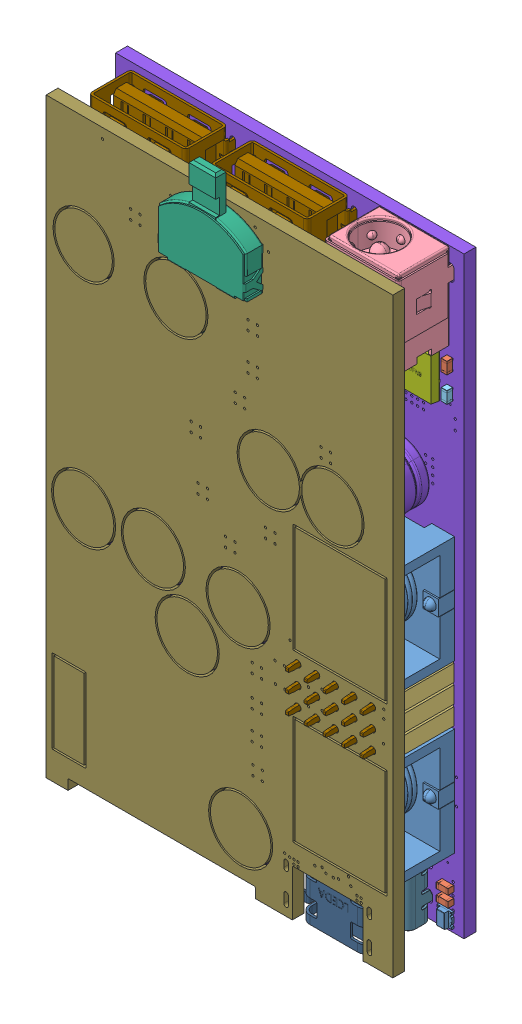
SolidWorks assembly YDS, configuration 默认. Lengths in mm.
Overall size (47.39 84.33 15.15).
408 component instances, 34 part files, 3 mates.
Components (placement in the parent):
- 3D_1_PCB_YDS-Charger_2022-04-09_2022-04-09-1: 3D_1_PCB_YDS-Charger_2022-04-09_2022-04-09 [Default] at (-64.0814 58.5784 -4.3265) size (47.39 99.44 11.55)
  - 3D_1_PCB_YDS-Charger_2022-04-09_2022-04-09.step-1: 3D_1_PCB_YDS-Charger_2022-04-09_2022-04-09.step [Default] at origin size (47.39 99.44 11.55)
    - LED1.step-1: LED1.step [Default] at (44.6406 -78.4544 1.6) x (-1 0 0) z (0 0 1) size (2 2 0.84)
      - LED-SMD_4P-L2.0-W2.0-TL_WS2812B-2020.step-1: LED-SMD_4P-L2.0-W2.0-TL_WS2812B-2020.step [Default] at (0 0.0001 0.02) size (2 2 0.84)
        - COMPOUND.step-1: COMPOUND.step [Default] at origin size (2 2 0.84)
    - LED2.step-1: LED2.step [Default] at (31.5596 -78.4544 1.6) x (-1 0 0) z (0 0 1) size (2 2 0.84)
      - LED-SMD_4P-L2.0-W2.0-TL_WS2812B-2020.step-1: LED-SMD_4P-L2.0-W2.0-TL_WS2812B-2020.step [Default] at (0 0.0001 0.02) size (2 2 0.84)
        - COMPOUND.step-1: COMPOUND.step [Default] at origin size (2 2 0.84)
    - C28.step-1: C28.step [Default] at (29.8451 -61.5951 1.6) x (0 1 0) z (0 0 1) size (1.6 0.8 0.8)
      - C0603.step-1: C0603.step [Default] at (0 0 0.4) size (1.6 0.8 0.8)
        - SOLID.step-1: SOLID.step [Default] at origin size (1.6 0.8 0.8)
    - C49.step-1: C49.step [Default] at (19.05 -42.6721 1.6) x (-0.707107 0.707107 0) z (0 0 1) size (1.6 0.8 0.8)
      - C0603.step-1: C0603.step [Default] at (0 0 0.4) size (1.6 0.8 0.8)
        - SOLID.step-1: SOLID.step [Default] at origin size (1.6 0.8 0.8)
    - C51.step-1: C51.step [Default] at (24.645 -14.859 1.6) x (-1 0 0) z (0 0 1) size (1.6 0.8 0.8)
      - C0603.step-1: C0603.step [Default] at (0 0 0.4) size (1.6 0.8 0.8)
        - SOLID.step-1: SOLID.step [Default] at origin size (1.6 0.8 0.8)
    - C38.step-1: C38.step [Default] at (30.9246 -50.2921 1.6) size (1.6 0.8 0.8)
      - C0603.step-1: C0603.step [Default] at (0 0 0.4) size (1.6 0.8 0.8)
        - SOLID.step-1: SOLID.step [Default] at origin size (1.6 0.8 0.8)
    - C54.step-1: C54.step [Default] at (17.653 -60.4521 1.6) size (1.6 0.8 0.8)
      - C0603.step-1: C0603.step [Default] at (0 0 0.4) size (1.6 0.8 0.8)
        - SOLID.step-1: SOLID.step [Default] at origin size (1.6 0.8 0.8)
    - C46.step-1: C46.step [Default] at (11.557 -14.859 1.6) x (-1 0 0) z (0 0 1) size (1.6 0.8 0.8)
      - C0603.step-1: C0603.step [Default] at (0 0 0.4) size (1.6 0.8 0.8)
        - SOLID.step-1: SOLID.step [Default] at origin size (1.6 0.8 0.8)
    - C26.step-1: C26.step [Default] at (44.8311 -76.3271 1.6) x (-1 0 0) z (0 0 1) size (1.6 0.8 0.8)
      - C0603.step-1: C0603.step [Default] at (0 0 0.4) size (1.6 0.8 0.8)
        - SOLID.step-1: SOLID.step [Default] at origin size (1.6 0.8 0.8)
    - C27.step-1: C27.step [Default] at (44.8311 -74.8031 1.6) x (-1 0 0) z (0 0 1) size (1.6 0.8 0.8)
      - C0603.step-1: C0603.step [Default] at (0 0 0.4) size (1.6 0.8 0.8)
        - SOLID.step-1: SOLID.step [Default] at origin size (1.6 0.8 0.8)
    - C29.step-1: C29.step [Default] at (29.2101 -76.9304 1.6) x (0.866025 0.5 0) z (0 0 1) size (1.6 0.8 0.8)
      - C0603.step-1: C0603.step [Default] at (0 0 0.4) size (1.6 0.8 0.8)
        - SOLID.step-1: SOLID.step [Default] at origin size (1.6 0.8 0.8)
    - C39.step-1: C39.step [Default] at (29.7181 -38.5091 1.6) x (0 1 0) z (0 0 1) size (1.6 0.8 0.8)
      - C0603.step-1: C0603.step [Default] at (0 0 0.4) size (1.6 0.8 0.8)
        - SOLID.step-1: SOLID.step [Default] at origin size (1.6 0.8 0.8)
    - C22.step-1: C22.step [Default] at (9.398 -42.5451 1.6) x (-0.707107 0.707107 0) z (0 0 1) size (1.6 0.8 0.8)
      - C0603.step-1: C0603.step [Default] at (0 0 0.4) size (1.6 0.8 0.8)
        - SOLID.step-1: SOLID.step [Default] at origin size (1.6 0.8 0.8)
    - C45.step-1: C45.step [Default] at (3.048 -40.1321 1.6) x (0 1 0) z (0 0 1) size (1.6 0.8 0.8)
      - C0603.step-1: C0603.step [Default] at (0 0 0.4) size (1.6 0.8 0.8)
        - SOLID.step-1: SOLID.step [Default] at origin size (1.6 0.8 0.8)
    - C47.step-1: C47.step [Default] at (3.0425 -33.9526 1.6) x (0 -1 0) z (0 0 1) size (1.6 0.8 0.8)
      - C0603.step-1: C0603.step [Default] at (0 0 0.4) size (1.6 0.8 0.8)
        - SOLID.step-1: SOLID.step [Default] at origin size (1.6 0.8 0.8)
    - C48.step-1: C48.step [Default] at (12.0333 -33.9526 1.6) x (0 -1 0) z (0 0 1) size (1.6 0.8 0.8)
      - C0603.step-1: C0603.step [Default] at (0 0 0.4) size (1.6 0.8 0.8)
        - SOLID.step-1: SOLID.step [Default] at origin size (1.6 0.8 0.8)
    - C52.step-1: C52.step [Default] at (12.0386 -40.1321 1.6) x (0 1 0) z (0 0 1) size (1.6 0.8 0.8)
      - C0603.step-1: C0603.step [Default] at (0 0 0.4) size (1.6 0.8 0.8)
        - SOLID.step-1: SOLID.step [Default] at origin size (1.6 0.8 0.8)
    - C13.step-1: C13.step [Default] at (8.763 -73.7871 1.6) x (0 1 0) z (0 0 1) size (1.6 0.8 0.8)
      - C0603.step-1: C0603.step [Default] at (0 0 0.4) size (1.6 0.8 0.8)
        - SOLID.step-1: SOLID.step [Default] at origin size (1.6 0.8 0.8)
    - C6.step-1: C6.step [Default] at (21.59 -76.9621 1.6) x (0 -1 0) z (0 0 1) size (1.6 0.8 0.8)
      - C0603.step-1: C0603.step [Default] at (0 0 0.4) size (1.6 0.8 0.8)
        - SOLID.step-1: SOLID.step [Default] at origin size (1.6 0.8 0.8)
    - C58.step-1: C58.step [Default] at (5.715 -51.4351 1.6) size (1.6 0.8 0.8)
      - C0603.step-1: C0603.step [Default] at (0 0 0.4) size (1.6 0.8 0.8)
        - SOLID.step-1: SOLID.step [Default] at origin size (1.6 0.8 0.8)
    - C40.step-1: C40.step [Default] at (21.971 -41.0491 1.6) size (1.6 0.8 0.8)
      - C0603.step-1: C0603.step [Default] at (0 0 0.4) size (1.6 0.8 0.8)
        - SOLID.step-1: SOLID.step [Default] at origin size (1.6 0.8 0.8)
    - C24.step-1: C24.step [Default] at (26.7971 -65.2781 1.6) size (1.6 0.8 0.8)
      - C0603.step-1: C0603.step [Default] at (-0.0001 0 0.4) size (1.6 0.8 0.8)
        - SOLID.step-1: SOLID.step [Default] at origin size (1.6 0.8 0.8)
    - C30.step-1: C30.step [Default] at (29.0831 -58.0671 1.6) size (1.6 0.8 0.8)
      - C0603.step-1: C0603.step [Default] at (0 0 0.4) size (1.6 0.8 0.8)
        - SOLID.step-1: SOLID.step [Default] at origin size (1.6 0.8 0.8)
    - C31.step-1: C31.step [Default] at (25.6541 -58.0671 1.6) size (1.6 0.8 0.8)
      - C0603.step-1: C0603.step [Default] at (0 0 0.4) size (1.6 0.8 0.8)
        - SOLID.step-1: SOLID.step [Default] at origin size (1.6 0.8 0.8)
    - C32.step-1: C32.step [Default] at (22.86 -62.0041 1.6) x (0 1 0) z (0 0 1) size (1.6 0.8 0.8)
      - C0603.step-1: C0603.step [Default] at (0 0 0.4) size (1.6 0.8 0.8)
        - SOLID.step-1: SOLID.step [Default] at origin size (1.6 0.8 0.8)
    - C35.step-1: C35.step [Default] at (21.971 -37.4931 1.6) size (1.6 0.8 0.8)
      - C0603.step-1: C0603.step [Default] at (-0.0001 0 0.4) size (1.6 0.8 0.8)
        - SOLID.step-1: SOLID.step [Default] at origin size (1.6 0.8 0.8)
    - C36.step-1: C36.step [Default] at (27.9401 -34.163 1.6) x (0 1 0) z (0 0 1) size (1.6 0.8 0.8)
      - C0603.step-1: C0603.step [Default] at (0 -0.0001 0.4) size (1.6 0.8 0.8)
        - SOLID.step-1: SOLID.step [Default] at origin size (1.6 0.8 0.8)
    - C37.step-1: C37.step [Default] at (29.7181 -35.4611 1.6) x (0 -1 0) z (0 0 1) size (1.6 0.8 0.8)
      - C0603.step-1: C0603.step [Default] at (0 0.0001 0.4) size (1.6 0.8 0.8)
        - SOLID.step-1: SOLID.step [Default] at origin size (1.6 0.8 0.8)
    - C41.step-1: C41.step [Default] at (21.971 -39.2711 1.6) size (1.6 0.8 0.8)
      - C0603.step-1: C0603.step [Default] at (0 0 0.4) size (1.6 0.8 0.8)
        - SOLID.step-1: SOLID.step [Default] at origin size (1.6 0.8 0.8)
    - C43.step-1: C43.step [Default] at (24.638 -53.0861 1.6) x (0 1 0) z (0 0 1) size (1.6 0.8 0.8)
      - C0603.step-1: C0603.step [Default] at (0 -0.0001 0.4) size (1.6 0.8 0.8)
        - SOLID.step-1: SOLID.step [Default] at origin size (1.6 0.8 0.8)
    - C7.step-1: C7.step [Default] at (20.828 -73.1521 1.6) size (1.6 0.8 0.8)
      - C0603.step-1: C0603.step [Default] at (0 0 0.4) size (1.6 0.8 0.8)
        - SOLID.step-1: SOLID.step [Default] at origin size (1.6 0.8 0.8)
    - C14.step-1: C14.step [Default] at (10.414 -73.7871 1.6) x (0 1 0) z (0 0 1) size (1.6 0.8 0.8)
      - C0603.step-1: C0603.step [Default] at (0 0 0.4) size (1.6 0.8 0.8)
        - SOLID.step-1: SOLID.step [Default] at origin size (1.6 0.8 0.8)
    - C15.step-1: C15.step [Default] at (14.986 -67.2112 1.6) x (-1 0 0) z (0 0 1) size (1.6 0.8 0.8)
      - C0603.step-1: C0603.step [Default] at (0 0 0.4) size (1.6 0.8 0.8)
        - SOLID.step-1: SOLID.step [Default] at origin size (1.6 0.8 0.8)
    - C16.step-1: C16.step [Default] at (18.034 -67.2112 1.6) size (1.6 0.8 0.8)
      - C0603.step-1: C0603.step [Default] at (0 0 0.4) size (1.6 0.8 0.8)
        - SOLID.step-1: SOLID.step [Default] at origin size (1.6 0.8 0.8)
    - C17.step-1: C17.step [Default] at (18.288 -76.9621 1.6) x (0 1 0) z (0 0 1) size (1.6 0.8 0.8)
      - C0603.step-1: C0603.step [Default] at (0 0 0.4) size (1.6 0.8 0.8)
        - SOLID.step-1: SOLID.step [Default] at origin size (1.6 0.8 0.8)
    - C18.step-1: C18.step [Default] at (15.875 -76.2001 1.6) size (1.6 0.8 0.8)
      - C0603.step-1: C0603.step [Default] at (0 0 0.4) size (1.6 0.8 0.8)
        - SOLID.step-1: SOLID.step [Default] at origin size (1.6 0.8 0.8)
    - C19.step-1: C19.step [Default] at (6.096 -71.1482 1.6) x (0 -1 0) z (0 0 1) size (1.6 0.8 0.8)
      - C0603.step-1: C0603.step [Default] at (0 0 0.4) size (1.6 0.8 0.8)
        - SOLID.step-1: SOLID.step [Default] at origin size (1.6 0.8 0.8)
    - C20.step-1: C20.step [Default] at (6.096 -67.9732 1.6) x (0 1 0) z (0 0 1) size (1.6 0.8 0.8)
      - C0603.step-1: C0603.step [Default] at (0 0 0.4) size (1.6 0.8 0.8)
        - SOLID.step-1: SOLID.step [Default] at origin size (1.6 0.8 0.8)
    - C55.step-1: C55.step [Default] at (9.525 -55.1181 1.6) size (1.6 0.8 0.8)
      - C0603.step-1: C0603.step [Default] at (0 0 0.4) size (1.6 0.8 0.8)
        - SOLID.step-1: SOLID.step [Default] at origin size (1.6 0.8 0.8)
    - C56.step-1: C56.step [Default] at (9.525 -56.8961 1.6) x (-1 0 0) z (0 0 1) size (1.6 0.8 0.8)
      - C0603.step-1: C0603.step [Default] at (0 0 0.4) size (1.6 0.8 0.8)
        - SOLID.step-1: SOLID.step [Default] at origin size (1.6 0.8 0.8)
    - C57.step-1: C57.step [Default] at (9.906 -49.7841 1.6) size (1.6 0.8 0.8)
      - C0603.step-1: C0603.step [Default] at (0 0 0.4) size (1.6 0.8 0.8)
        - SOLID.step-1: SOLID.step [Default] at origin size (1.6 0.8 0.8)
    - C2.step-1: C2.step [Default] at (3.937 -63.5001 1.6) x (0 1 0) z (0 0 1) size (1.6 0.8 0.8)
      - C0603.step-1: C0603.step [Default] at (0 0 0.4) size (1.6 0.8 0.8)
        - SOLID.step-1: SOLID.step [Default] at origin size (1.6 0.8 0.8)
    - C3.step-1: C3.step [Default] at (2.413 -63.5001 1.6) x (0 1 0) z (0 0 1) size (1.6 0.8 0.8)
      - C0603.step-1: C0603.step [Default] at (0 0 0.4) size (1.6 0.8 0.8)
        - SOLID.step-1: SOLID.step [Default] at origin size (1.6 0.8 0.8)
    - C8.step-1: C8.step [Default] at (5.461 -63.5001 1.6) x (0 1 0) z (0 0 1) size (1.6 0.8 0.8)
      - C0603.step-1: C0603.step [Default] at (0 0 0.4) size (1.6 0.8 0.8)
        - SOLID.step-1: SOLID.step [Default] at origin size (1.6 0.8 0.8)
    - C9.step-1: C9.step [Default] at (6.985 -63.5001 1.6) x (0 1 0) z (0 0 1) size (1.6 0.8 0.8)
      - C0603.step-1: C0603.step [Default] at (0 0 0.4) size (1.6 0.8 0.8)
        - SOLID.step-1: SOLID.step [Default] at origin size (1.6 0.8 0.8)
    - C10.step-1: C10.step [Default] at (22.733 -65.3061 1.6) x (0 1 0) z (0 0 1) size (1.6 0.8 0.8)
      - C0603.step-1: C0603.step [Default] at (0 0 0.4) size (1.6 0.8 0.8)
        - SOLID.step-1: SOLID.step [Default] at origin size (1.6 0.8 0.8)
    - C11.step-1: C11.step [Default] at (20.701 -65.3061 1.6) x (0 1 0) z (0 0 1) size (1.6 0.8 0.8)
      - C0603.step-1: C0603.step [Default] at (0 0 0.4) size (1.6 0.8 0.8)
        - SOLID.step-1: SOLID.step [Default] at origin size (1.6 0.8 0.8)
    - C12.step-1: C12.step [Default] at (10.795 -64.2901 1.6) x (-1 0 0) z (0 0 1) size (1.6 0.8 0.8)
      - C0603.step-1: C0603.step [Default] at (0 0 0.4) size (1.6 0.8 0.8)
        - SOLID.step-1: SOLID.step [Default] at origin size (1.6 0.8 0.8)
    - C63.step-1: C63.step [Default] at (45.0851 -13.716 1.6) x (0 1 0) z (0 0 1) size (1.6 0.8 0.8)
      - C0603.step-1: C0603.step [Default] at (0 0 0.4) size (1.6 0.8 0.8)
        - SOLID.step-1: SOLID.step [Default] at origin size (1.6 0.8 0.8)
    - C53.step-1: C53.step [Default] at (13.97 -56.0072 1.6) x (0 -1 0) z (0 0 1) size (1.6 0.8 0.8)
      - C0603.step-1: C0603.step [Default] at (0 0 0.4) size (1.6 0.8 0.8)
        - SOLID.step-1: SOLID.step [Default] at origin size (1.6 0.8 0.8)
    - U3.step-1: U3.step [Default] at (7.366 -36.957 1.6) x (-1 0 0) z (0 0 1) size (4.9 3.9 1.6)
      - ESOP-8_L4.9-W3.9-P1.27-LS6.0-BL-EP.step-1: ESOP-8_L4.9-W3.9-P1.27-LS6.0-BL-EP.step [Default] at (0 0 0.0993) x (0 1 0) z (0 0 1) size (3.9 4.9 1.6)
        - =_[0_1_1_59].step-1: =_[0_1_1_59].step [Default] at origin size (3.9 4.9 1.6)
    - U8.step-1: U8.step [Default] at (15.621 -36.9851 1.6) x (-1 0 0) z (0 0 1) size (4.9 3.9 1.6)
      - ESOP-8_L4.9-W3.9-P1.27-LS6.0-BL-EP.step-1: ESOP-8_L4.9-W3.9-P1.27-LS6.0-BL-EP.step [Default] at (0 0 0.0993) x (0 1 0) z (0 0 1) size (3.9 4.9 1.6)
        - =_[0_1_1_59].step-1: =_[0_1_1_59].step [Default] at origin size (3.9 4.9 1.6)
    - C33.step-1: C33.step [Default] at (20.828 -61.6231 1.6) x (0 1 0) z (0 0 1) size (2 1.3 1.3)
      - C0805.step-1: C0805.step [Default] at (0 0 0.65) size (2 1.3 1.3)
        - SOLID-0.step-1: SOLID-0.step [Default] at origin size (2 1.3 1.3)
    - C34.step-1: C34.step [Default] at (24.13 -12.954 1.6) size (2 1.3 1.3)
      - C0805.step-1: C0805.step [Default] at (0 0.0001 0.65) size (2 1.3 1.3)
        - SOLID-0.step-1: SOLID-0.step [Default] at origin size (2 1.3 1.3)
    - C62.step-1: C62.step [Default] at (11.684 -12.954 1.6) x (-1 0 0) z (0 0 1) size (2 1.3 1.3)
      - C0805.step-1: C0805.step [Default] at (0 0 0.65) size (2 1.3 1.3)
        - SOLID-0.step-1: SOLID-0.step [Default] at origin size (2 1.3 1.3)
    - C42.step-1: C42.step [Default] at (26.7971 -53.4671 1.6) x (0 1 0) z (0 0 1) size (2 1.3 1.3)
      - C0805.step-1: C0805.step [Default] at (0 0 0.65) size (2 1.3 1.3)
        - SOLID-0.step-1: SOLID-0.step [Default] at origin size (2 1.3 1.3)
    - C25.step-1: C25.step [Default] at (28.5751 -67.4371 1.6) size (2 1.3 1.3)
      - C0805.step-1: C0805.step [Default] at (0 0.0001 0.65) size (2 1.3 1.3)
        - SOLID-0.step-1: SOLID-0.step [Default] at origin size (2 1.3 1.3)
    - C23.step-1: C23.step [Default] at (21.717 -35.2071 1.6) size (2 1.3 1.3)
      - C0805.step-1: C0805.step [Default] at (0 0 0.65) size (2 1.3 1.3)
        - SOLID-0.step-1: SOLID-0.step [Default] at origin size (2 1.3 1.3)
    - C64.step-1: C64.step [Default] at (36.0681 -18.669 1.6) x (-1 0 0) z (0 0 1) size (2 1.3 1.3)
      - C0805.step-1: C0805.step [Default] at (0 0 0.65) size (2 1.3 1.3)
        - SOLID-0.step-1: SOLID-0.step [Default] at origin size (2 1.3 1.3)
    - R2.step-1: R2.step [Default] at (29.8451 -64.5161 1.6) x (0 -1 0) z (0 0 1) size (1.6 0.8 0.8)
      - R0603.step-1: R0603.step [Default] at (0 0 0.4) size (1.6 0.8 0.8)
        - SOLID-1.step-1: SOLID-1.step [Default] at origin size (1.6 0.8 0.8)
    - R15.step-1: R15.step [Default] at (29.7181 -41.5571 1.6) x (0 -1 0) z (0 0 1) size (1.6 0.8 0.8)
      - R0603.step-1: R0603.step [Default] at (0 -0.0001 0.4) size (1.6 0.8 0.8)
        - SOLID-1.step-1: SOLID-1.step [Default] at origin size (1.6 0.8 0.8)
    - R16.step-1: R16.step [Default] at (3.048 -37.084 1.6) x (0 -1 0) z (0 0 1) size (1.6 0.8 0.8)
      - R0603.step-1: R0603.step [Default] at (0 0 0.4) size (1.6 0.8 0.8)
        - SOLID-1.step-1: SOLID-1.step [Default] at origin size (1.6 0.8 0.8)
    - R13.step-1: R13.step [Default] at (12.0333 -37.0523 1.6) x (0 -1 0) z (0 0 1) size (1.6 0.8 0.8)
      - R0603.step-1: R0603.step [Default] at (0 0 0.4) size (1.6 0.8 0.8)
        - SOLID-1.step-1: SOLID-1.step [Default] at origin size (1.6 0.8 0.8)
    - R1.step-1: R1.step [Default] at (20.828 -74.6761 1.6) x (-1 0 0) z (0 0 1) size (1.6 0.8 0.8)
      - R0603.step-1: R0603.step [Default] at (0 0 0.4) size (1.6 0.8 0.8)
        - SOLID-1.step-1: SOLID-1.step [Default] at origin size (1.6 0.8 0.8)
    - R6.step-1: R6.step [Default] at (19.939 -76.9621 1.6) x (0 -1 0) z (0 0 1) size (1.6 0.8 0.8)
      - R0603.step-1: R0603.step [Default] at (0 0 0.4) size (1.6 0.8 0.8)
        - SOLID-1.step-1: SOLID-1.step [Default] at origin size (1.6 0.8 0.8)
    - R4.step-1: R4.step [Default] at (20.828 -70.2311 1.6) size (1.6 0.8 0.8)
      - R0603.step-1: R0603.step [Default] at (0 0 0.4) size (1.6 0.8 0.8)
        - SOLID-1.step-1: SOLID-1.step [Default] at origin size (1.6 0.8 0.8)
    - R5.step-1: R5.step [Default] at (23.0188 -58.7058 1.6) x (0 1 0) z (0 0 1) size (1.6 0.8 0.8)
      - R0603.step-1: R0603.step [Default] at (0 0 0.4) size (1.6 0.8 0.8)
        - SOLID-1.step-1: SOLID-1.step [Default] at origin size (1.6 0.8 0.8)
    - R12.step-1: R12.step [Default] at (25.5271 -34.925 1.6) size (1.6 0.8 0.8)
      - R0603.step-1: R0603.step [Default] at (0.0001 0 0.4) size (1.6 0.8 0.8)
        - SOLID-1.step-1: SOLID-1.step [Default] at origin size (1.6 0.8 0.8)
    - R7.step-1: R7.step [Default] at (8.509 -63.5281 1.6) x (0 1 0) z (0 0 1) size (1.6 0.8 0.8)
      - R0603.step-1: R0603.step [Default] at (0 0 0.4) size (1.6 0.8 0.8)
        - SOLID-1.step-1: SOLID-1.step [Default] at origin size (1.6 0.8 0.8)
    - R8.step-1: R8.step [Default] at (14.605 -63.5485 1.6) x (0 -1 0) z (0 0 1) size (1.6 0.8 0.8)
      - R0603.step-1: R0603.step [Default] at (0 0 0.4) size (1.6 0.8 0.8)
        - SOLID-1.step-1: SOLID-1.step [Default] at origin size (1.6 0.8 0.8)
    - R9.step-1: R9.step [Default] at (13.081 -63.5485 1.6) x (0 1 0) z (0 0 1) size (1.6 0.8 0.8)
      - R0603.step-1: R0603.step [Default] at (0 0 0.4) size (1.6 0.8 0.8)
        - SOLID-1.step-1: SOLID-1.step [Default] at origin size (1.6 0.8 0.8)
    - R10.step-1: R10.step [Default] at (20.828 -68.8341 1.6) x (-1 0 0) z (0 0 1) size (1.6 0.8 0.8)
      - R0603.step-1: R0603.step [Default] at (0 0 0.4) size (1.6 0.8 0.8)
        - SOLID-1.step-1: SOLID-1.step [Default] at origin size (1.6 0.8 0.8)
    - R11.step-1: R11.step [Default] at (10.795 -62.6391 1.6) x (-1 0 0) z (0 0 1) size (1.6 0.8 0.8)
      - R0603.step-1: R0603.step [Default] at (0 0 0.4) size (1.6 0.8 0.8)
        - SOLID-1.step-1: SOLID-1.step [Default] at origin size (1.6 0.8 0.8)
    - R19.step-1: R19.step [Default] at (45.0851 -17.145 1.6) x (0 -1 0) z (0 0 1) size (1.6 0.8 0.8)
      - R0603.step-1: R0603.step [Default] at (0 0 0.4) size (1.6 0.8 0.8)
        - SOLID-1.step-1: SOLID-1.step [Default] at origin size (1.6 0.8 0.8)
    - R20.step-1: R20.step [Default] at (32.2581 -18.669 1.6) x (-1 0 0) z (0 0 1) size (1.6 0.8 0.8)
      - R0603.step-1: R0603.step [Default] at (0 0 0.4) size (1.6 0.8 0.8)
        - SOLID-1.step-1: SOLID-1.step [Default] at origin size (1.6 0.8 0.8)
    - R21.step-1: R21.step [Default] at (36.3221 -20.574 1.6) x (-1 0 0) z (0 0 1) size (1.6 0.8 0.8)
      - R0603.step-1: R0603.step [Default] at (0 0 0.4) size (1.6 0.8 0.8)
        - SOLID-1.step-1: SOLID-1.step [Default] at origin size (1.6 0.8 0.8)
    - R22.step-1: R22.step [Default] at (11.557 -16.637 1.6) size (1.6 0.8 0.8)
      - R0603.step-1: R0603.step [Default] at (0 0 0.4) size (1.6 0.8 0.8)
        - SOLID-1.step-1: SOLID-1.step [Default] at origin size (1.6 0.8 0.8)
    - R23.step-1: R23.step [Default] at (11.557 -18.288 1.6) x (-1 0 0) z (0 0 1) size (1.6 0.8 0.8)
      - R0603.step-1: R0603.step [Default] at (0 0 0.4) size (1.6 0.8 0.8)
        - SOLID-1.step-1: SOLID-1.step [Default] at origin size (1.6 0.8 0.8)
    - R24.step-1: R24.step [Default] at (20.828 -71.5646 1.6) size (1.6 0.8 0.8)
      - R0603.step-1: R0603.step [Default] at (0 0 0.4) size (1.6 0.8 0.8)
        - SOLID-1.step-1: SOLID-1.step [Default] at origin size (1.6 0.8 0.8)
    - R25.step-1: R25.step [Default] at (24.7015 -16.4465 1.6) size (1.6 0.8 0.8)
      - R0603.step-1: R0603.step [Default] at (0 0 0.4) size (1.6 0.8 0.8)
        - SOLID-1.step-1: SOLID-1.step [Default] at origin size (1.6 0.8 0.8)
    - R26.step-1: R26.step [Default] at (24.7015 -18.034 1.6) x (-1 0 0) z (0 0 1) size (1.6 0.8 0.8)
      - R0603.step-1: R0603.step [Default] at (0 0 0.4) size (1.6 0.8 0.8)
        - SOLID-1.step-1: SOLID-1.step [Default] at origin size (1.6 0.8 0.8)
    - R17.step-1: R17.step [Default] at (12.446 -56.0071 1.6) x (0 1 0) z (0 0 1) size (1.6 0.8 0.8)
      - R0603.step-1: R0603.step [Default] at (0 0 0.4) size (1.6 0.8 0.8)
        - SOLID-1.step-1: SOLID-1.step [Default] at origin size (1.6 0.8 0.8)
    - R18.step-1: R18.step [Default] at (12.446 -52.8638 1.6) x (0 1 0) z (0 0 1) size (1.6 0.8 0.8)
      - R0603.step-1: R0603.step [Default] at (0 0 0.4) size (1.6 0.8 0.8)
        - SOLID-1.step-1: SOLID-1.step [Default] at origin size (1.6 0.8 0.8)
    - R14.step-1: R14.step [Default] at (30.3531 -52.4511 1.6) x (-1 0 0) z (0 0 1) size (3.2 1.6 0.56)
      - R1206.step-1: R1206.step [Default] at origin size (3.2 1.6 0.56)
        - COMPOUND-2.step-1: COMPOUND-2.step [Default] at origin size (3.2 1.6 0.56)
    - R3.step-1: R3.step [Default] at (31.7501 -74.0411 1.6) x (0 -1 0) z (0 0 1) size (3.2 1.6 0.56)
      - R1206.step-1: R1206.step [Default] at origin size (3.2 1.6 0.56)
        - COMPOUND-2.step-1: COMPOUND-2.step [Default] at origin size (3.2 1.6 0.56)
    - U9.step-1: U9.step [Default] at (17.653 -63.3731 1.6) size (3 3 0.92)
      - LGA-16_L3.0-W3.0-P0.50-TL.step-1: LGA-16_L3.0-W3.0-P0.50-TL.step [Default] at (0.0001 0.0001 0) size (3 3 0.92)
        - COMPOUND-3.step-1: COMPOUND-3.step [Default] at origin size (3 3 0.92)
    - C4.step-1: C4.step [Default] at (30.4166 -28.956 1.6) x (0.707107 0.707107 0) z (0 0 1) size (8 8 11.5)
      - CAP-TH_BD8.0-P3.50-D0.6-FD.step-1: CAP-TH_BD8.0-P3.50-D0.6-FD.step [Default] at (0.1475 0.1475 0.5) x (-1 0 0) z (0 0 1) size (8 8 11.5)
        - SOLID-4.step-1: SOLID-4.step [Default] at origin size (8 8 11.5)
    - C21.step-1: C21.step [Default] at (5.461 -15.113 1.6) x (-0.707107 0.707107 0) z (0 0 1) size (8 8 11.5)
      - CAP-TH_BD8.0-P3.50-D0.6-FD.step-1: CAP-TH_BD8.0-P3.50-D0.6-FD.step [Default] at (0.1475 0.1475 0.5) x (-1 0 0) z (0 0 1) size (8 8 11.5)
        - SOLID-4.step-1: SOLID-4.step [Default] at origin size (8 8 11.5)
    - C50.step-1: C50.step [Default] at (17.907 -15.113 1.6) x (-0.707107 0.707107 0) z (0 0 1) size (8 8 11.5)
      - CAP-TH_BD8.0-P3.50-D0.6-FD.step-1: CAP-TH_BD8.0-P3.50-D0.6-FD.step [Default] at (0.1475 0.1475 0.5) x (-1 0 0) z (0 0 1) size (8 8 11.5)
        - SOLID-4.step-1: SOLID-4.step [Default] at origin size (8 8 11.5)
    - C59.step-1: C59.step [Default] at (14.859 -45.8751 1.6) x (-0.707107 -0.707107 0) z (0 0 1) size (8 8 11.5)
      - CAP-TH_BD8.0-P3.50-D0.6-FD.step-1: CAP-TH_BD8.0-P3.50-D0.6-FD.step [Default] at (0.1475 0.1475 0.5) x (-1 0 0) z (0 0 1) size (8 8 11.5)
        - SOLID-4.step-1: SOLID-4.step [Default] at origin size (8 8 11.5)
    - C60.step-1: C60.step [Default] at (5.461 -45.8471 1.6) x (-0.707107 -0.707107 0) z (0 0 1) size (8 8 11.5)
      - CAP-TH_BD8.0-P3.50-D0.6-FD.step-1: CAP-TH_BD8.0-P3.50-D0.6-FD.step [Default] at (0.1475 0.1475 0.5) x (-1 0 0) z (0 0 1) size (8 8 11.5)
        - SOLID-4.step-1: SOLID-4.step [Default] at origin size (8 8 11.5)
    - C61.step-1: C61.step [Default] at (19.431 -53.7491 1.6) x (-0.707107 0.707107 0) z (0 0 1) size (8 8 11.5)
      - CAP-TH_BD8.0-P3.50-D0.6-FD.step-1: CAP-TH_BD8.0-P3.50-D0.6-FD.step [Default] at (0.1475 0.1475 0.5) x (-1 0 0) z (0 0 1) size (8 8 11.5)
        - SOLID-4.step-1: SOLID-4.step [Default] at origin size (8 8 11.5)
    - C44.step-1: C44.step [Default] at (26.2891 -46.9901 1.6) x (-0.707107 -0.707107 0) z (0 0 1) size (8 8 11.5)
      - CAP-TH_BD8.0-P3.50-D0.6-FD.step-1: CAP-TH_BD8.0-P3.50-D0.6-FD.step [Default] at (0.1475 0.1475 0.5) x (-1 0 0) z (0 0 1) size (8 8 11.5)
        - SOLID-4.step-1: SOLID-4.step [Default] at origin size (8 8 11.5)
    - C1.step-1: C1.step [Default] at (26.6383 -72.6441 1.6) x (-0.707107 -0.707107 0) z (0 0 1) size (8 8 11.5)
      - CAP-TH_BD8.0-P3.50-D0.6-FD.step-1: CAP-TH_BD8.0-P3.50-D0.6-FD.step [Default] at (0.1475 0.1475 0.5) x (-1 0 0) z (0 0 1) size (8 8 11.5)
        - SOLID-4.step-1: SOLID-4.step [Default] at origin size (8 8 11.5)
    - C65.step-1: C65.step [Default] at (38.8938 -28.956 1.6) x (0.707107 0.707107 0) z (0 0 1) size (8 8 11.5)
      - CAP-TH_BD8.0-P3.50-D0.6-FD.step-1: CAP-TH_BD8.0-P3.50-D0.6-FD.step [Default] at (0.1475 0.1475 0.5) x (-1 0 0) z (0 0 1) size (8 8 11.5)
        - SOLID-4.step-1: SOLID-4.step [Default] at origin size (8 8 11.5)
    - USB3.step-1: USB3.step [Default] at (9.398 -6.378 1.6) x (-1 0 0) z (0 0 1) size (14.3 10 8.5)
      - USB-A-TH_USB-240-BRW.step-1: USB-A-TH_USB-240-BRW.step [Default] at (0 -1.25 3.65) size (14.3 10 8.5)
        - COMPOUND-5.step-1: COMPOUND-5.step [Default] at origin size (14.3 10 8.5)
    - USB8.step-1: USB8.step [Default] at (25.7811 -6.378 1.6) x (-1 0 0) z (0 0 1) size (14.3 10 8.5)
      - USB-A-TH_USB-240-BRW.step-1: USB-A-TH_USB-240-BRW.step [Default] at (0 -1.25 3.65) size (14.3 10 8.5)
        - COMPOUND-5.step-1: COMPOUND-5.step [Default] at origin size (14.3 10 8.5)
    - OLED1.step-1: OLED1.step [Default] at (15.621 -68.7352 0) x (1 0 0) z (0 0 -1) size (26.7 31.27 1.42)
      - OLED_0.96-30P-P0.70-12864.step-1: OLED_0.96-30P-P0.70-12864.step [Default] at (0 22.9511 0.71) size (26.7 31.27 1.42)
        - COMPOUND-6.step-1: COMPOUND-6.step [Default] at origin size (26.7 31.27 1.42) (hidden)
    - BS.step-1: BS.step [Default] at (9.525 -52.4511 1.6) x (0 1 0) z (0 0 1) size (2.9 1.6 1.5)
      - SOT-23-6_L2.9-W1.6-P0.95-LS2.8-BL.step-1: SOT-23-6_L2.9-W1.6-P0.95-LS2.8-BL.step [Default] at (0 0 0.0486) x (0 1 0) z (0 0 1) size (1.6 2.9 1.5)
        - =_[0_1_1_124].step-1: =_[0_1_1_124].step [Default] at origin size (1.6 2.9 1.5)
    - U5.step-1: U5.step [Default] at (32.2581 -14.887 1.6) x (-1 0 0) z (0 0 1) size (9.99 5.71 6.23)
      - FUSE-SMD_L9.7-W5.0.step-1: FUSE-SMD_L9.7-W5.0.step [Default] at (0.3059 0 0) size (9.99 5.71 6.23)
        - =_[0_1_1_128].step-1: =_[0_1_1_128].step [Default] at (-0.3059 0 0.1) x (1 0 0) z (0 -1 0) size (9.73 3.71 5.03)
        - =_[0_1_1_130].step-1: =_[0_1_1_130].step [Default] at (-3.2509 0 0.1) x (1 0 0) z (0 -1 0) size (3.74 3.7 3.99)
        - =_[0_1_1_130].step-2: =_[0_1_1_130].step [Default] at (2.6391 0 0.1) x (-1 0 0) z (0 1 0) size (3.74 3.7 3.99)
        - =_[0_1_1_133].step-1: =_[0_1_1_133].step [Default] at (-3.8059 0 2.51) x (1 0 0) z (0 1 0) size (7.01 2.41 2.41)
    - USB1.step-1: USB1.step [Default] at (38.1001 -75.0001 1.6) size (8.94 7.9 4.1)
      - USB-C-SMD_TYPE-C16PIN.step-1: USB-C-SMD_TYPE-C16PIN.step [Default] at (0 -2.413 -0.15) x (-1 0 0) z (0 0 1) size (8.94 7.9 4.1)
        - SOLID-7.step-1: SOLID-7.step [Default] at origin size (8.94 7.9 4.1)
    - L6.step-1: L6.step [Default] at (7.493 -26.0631 1.6) x (0 -1 0) z (0 0 1) size (12 12 8)
      - IND-SMD_L12.0-W12.0_CDRH127NP.step-1: IND-SMD_L12.0-W12.0_CDRH127NP.step [Default] at (0 0 0.2) x (0 1 0) z (0 0 1) size (12 12 8)
        - COMPOUND-8.step-1: COMPOUND-8.step [Default] at origin size (12 12 8)
    - L5.step-1: L5.step [Default] at (19.685 -26.0631 1.6) x (0 -1 0) z (0 0 1) size (12 12 8)
      - IND-SMD_L12.0-W12.0_CDRH127NP.step-1: IND-SMD_L12.0-W12.0_CDRH127NP.step [Default] at (0 0 0.2) x (0 1 0) z (0 0 1) size (12 12 8)
        - COMPOUND-8.step-1: COMPOUND-8.step [Default] at origin size (12 12 8)
    - L3.step-1: L3.step [Default] at (15.875 -77.7241 1.6) x (-1 0 0) z (0 0 1) size (1.6 0.8 0.5)
      - L0603.step-1: L0603.step [Default] at (0.0024 0.016 0.25) x (-1 0 0) z (0 0 1) size (1.6 0.8 0.5)
        - SOLID-9.step-1: SOLID-9.step [Default] at origin size (1.6 0.8 0.5)
    - C5.step-1: C5.step [Default] at (5.588 -59.5911 1.6) size (3.7 2.8 2)
      - CASE-B_3528.step-1: CASE-B_3528.step [Default] at (0 0 1.049) size (3.7 2.8 2)
        - COMPOUND-10.step-1: COMPOUND-10.step [Default] at origin size (3.7 2.8 2)
    - L4.step-1: L4.step [Default] at (7.747 -76.9902 1.6) x (-1 0 0) z (0 0 1) size (9.5 2.1 1)
      - ANT-SMD_L9.5-W2.1.step-1: ANT-SMD_L9.5-W2.1.step [Default] at (0 0 0.01) size (9.5 2.1 1)
        - SOLID-11.step-1: SOLID-11.step [Default] at origin size (9.5 2.1 1)
    - L2.step-1: L2.step [Default] at (38.4811 -40.8941 1.6) size (14.5 14.5 8.01)
      - IND-SMD_L12.0-W12.0_CDRH127NP-1.step-1: IND-SMD_L12.0-W12.0_CDRH127NP-1.step [Default] at (0.0001 0 8.01) x (0 -1 0) z (0 0 1) size (14.5 14.5 8.01)
        - SOLID-12.step-1: SOLID-12.step [Default] at origin size (14.5 14.5 8.01)
    - L1.step-1: L1.step [Default] at (38.4811 -63.3451 1.6) size (14.5 14.5 8.01)
      - IND-SMD_L12.0-W12.0_CDRH127NP-1.step-1: IND-SMD_L12.0-W12.0_CDRH127NP-1.step [Default] at (0.0001 -0.0001 8.01) x (0 -1 0) z (0 0 1) size (14.5 14.5 8.01)
        - SOLID-12.step-1: SOLID-12.step [Default] at origin size (14.5 14.5 8.01)
    - U6.step-1: U6.step [Default] at (11.557 -60.7061 1.6) size (3.7 1.8 1.31)
      - SOD-123FL_L2.8-W1.7-LS3.6-RD.step-1: SOD-123FL_L2.8-W1.7-LS3.6-RD.step [Default] at (0 0 0.11) size (3.7 1.8 1.31)
        - COMPOUND-13.step-1: COMPOUND-13.step [Default] at origin size (3.7 1.8 1.31)
    - H2.step-1: H2.step [Default] at (34.2901 -52.1336 1.6) x (0 -1 0) z (0 0 1) size (7.62 2.54 11.5)
      - HDR-F-2.54_1X3.step-1: HDR-F-2.54_1X3.step [Default] at (2.54 0.0126 -0.048) size (7.62 2.54 11.5)
        - COMPOUND-14.step-1: COMPOUND-14.step [Default] at origin size (7.62 2.54 11.5)
    - H3.step-1: H3.step [Default] at (36.8301 -52.1336 1.6) x (0 -1 0) z (0 0 1) size (7.62 2.54 11.5)
      - HDR-F-2.54_1X3.step-1: HDR-F-2.54_1X3.step [Default] at (2.54 0.0126 -0.048) size (7.62 2.54 11.5)
        - COMPOUND-14.step-1: COMPOUND-14.step [Default] at origin size (7.62 2.54 11.5)
    - H4.step-1: H4.step [Default] at (41.8466 -52.1336 1.6) x (0 -1 0) z (0 0 1) size (7.62 2.54 11.5)
      - HDR-F-2.54_1X3.step-1: HDR-F-2.54_1X3.step [Default] at (2.54 0.0126 -0.048) size (7.62 2.54 11.5)
        - COMPOUND-14.step-1: COMPOUND-14.step [Default] at origin size (7.62 2.54 11.5)
    - H5.step-1: H5.step [Default] at (44.3548 -52.1336 1.6) x (0 -1 0) z (0 0 1) size (7.62 2.54 11.5)
      - HDR-F-2.54_1X3.step-1: HDR-F-2.54_1X3.step [Default] at (2.54 0.0126 -0.048) size (7.62 2.54 11.5)
        - COMPOUND-14.step-1: COMPOUND-14.step [Default] at origin size (7.62 2.54 11.5)
    - H6.step-1: H6.step [Default] at (39.3383 -52.1336 1.6) x (0 -1 0) z (0 0 1) size (7.62 2.54 11.5)
      - HDR-F-2.54_1X3.step-1: HDR-F-2.54_1X3.step [Default] at (2.54 0.0126 -0.048) size (7.62 2.54 11.5)
        - COMPOUND-14.step-1: COMPOUND-14.step [Default] at origin size (7.62 2.54 11.5)
    - DC2.step-1: DC2.step [Default] at (40.2591 -6.7033 1.6) x (0 -1 0) z (0 0 1) size (11.92 10.37 10.2)
      - DC-IN-TH_DC-044A-20A.step-1: DC-IN-TH_DC-044A-20A.step [Default] at (-0.8889 0.0639 0) size (11.92 10.37 10.2)
        - COMPOUND-15.step-1: COMPOUND-15.step [Default] at origin size (11.92 10.37 10.2)
    - U4.step-1: U4.step [Default] at (14.986 -71.6562 1.6) size (5 5 0.75)
      - QFN-32_L5.0-W5.0-P0.50-BL-EP3.7.step-1: QFN-32_L5.0-W5.0-P0.50-BL-EP3.7.step [Default] x (0 1 0) z (0 0 1) size (5 5 0.75)
        - COMPOUND-16.step-1: COMPOUND-16.step [Default] at origin size (5 5 0.75)
    - L7.step-1: L7.step [Default] at (4.8258 -54.9912 1.6) x (0 -1 0) z (0 0 1) size (4.46 4 3.21)
      - IND-SMD_L4.0-W4.0_CD43L-10UH.step-1: IND-SMD_L4.0-W4.0_CD43L-10UH.step [Default] at (0 0 0.01) size (4.46 4 3.21)
        - COMPOUND-17.step-1: COMPOUND-17.step [Default] at origin size (4.46 4 3.21)
    - Q1.step-1: Q1.step [Default] at (41.2751 -16.792 1.6) size (4.92 5.82 1.11)
      - POWERVDFN-8_L6.2-W5.2-P1.27-LS6.0-BL.step-1: POWERVDFN-8_L6.2-W5.2-P1.27-LS6.0-BL.step [Default] at (0 0.9249 0) x (0 1 0) z (0 0 1) size (5.82 4.92 1.11)
        - COMPOUND-18.step-1: COMPOUND-18.step [Default] at origin size (5.82 4.92 1.11)
    - COMPOUND-19.step-1: COMPOUND-19.step [Default] at origin size (46.97 79.97 1.6)
- 3D_2_PCB_Daughter-Board_2022-04-09_2022-04-09-1: 3D_2_PCB_Daughter-Board_2022-04-09_2022-04-09 [默认] at (-63.9671 58.6927 5.2735) size (46.75 84.23 12.55)
  - 3D_2_PCB_Daughter-Board_2022-04-09_2022-04-09.step-1: 3D_2_PCB_Daughter-Board_2022-04-09_2022-04-09.step [Default] at origin size (46.75 84.23 12.55)
    - LED1.step-1: LED1.step [Default] at (9.398 -2.032 0) x (1 0 0) z (0 0 -1) size (2 2 0.84)
      - LED-SMD_4P-L2.0-W2.0-TL_WS2812B-2020.step-1: LED-SMD_4P-L2.0-W2.0-TL_WS2812B-2020.step [Default] at (0 0.0001 0.02) size (2 2 0.84)
        - COMPOUND.step-1: COMPOUND.step [Default] at origin size (2 2 0.84)
    - LED2.step-1: LED2.step [Default] at (26.0986 -2.032 0) x (1 0 0) z (0 0 -1) size (2 2 0.84)
      - LED-SMD_4P-L2.0-W2.0-TL_WS2812B-2020.step-1: LED-SMD_4P-L2.0-W2.0-TL_WS2812B-2020.step [Default] at (0 0.0001 0.02) size (2 2 0.84)
        - COMPOUND.step-1: COMPOUND.step [Default] at origin size (2 2 0.84)
    - C1.step-1: C1.step [Default] at (25.9766 -7.2708 0) x (0 1 0) z (0 0 -1) size (1.6 0.8 0.8)
      - C0603.step-1: C0603.step [Default] at (0 0 0.4) size (1.6 0.8 0.8)
        - SOLID.step-1: SOLID.step [Default] at origin size (1.6 0.8 0.8)
    - C2.step-1: C2.step [Default] at (21.0236 -7.2708 0) x (0 1 0) z (0 0 -1) size (1.6 0.8 0.8)
      - C0603.step-1: C0603.step [Default] at (0 0 0.4) size (1.6 0.8 0.8)
        - SOLID.step-1: SOLID.step [Default] at origin size (1.6 0.8 0.8)
    - C17.step-1: C17.step [Default] at (23.5001 -7.2708 0) x (0 1 0) z (0 0 -1) size (1.6 0.8 0.8)
      - C0603.step-1: C0603.step [Default] at (0 0 0.4) size (1.6 0.8 0.8)
        - SOLID.step-1: SOLID.step [Default] at origin size (1.6 0.8 0.8)
    - H2.step-1: H2.step [Default] at (34.0411 -52.1336 0) x (0 -1 0) z (0 0 -1) size (7.62 2.54 11.5)
      - HDR-F-2.54_1X3.step-1: HDR-F-2.54_1X3.step [Default] at (2.54 0.0126 -0.048) size (7.62 2.54 11.5)
        - COMPOUND-0.step-1: COMPOUND-0.step [Default] at origin size (7.62 2.54 11.5)
    - H4.step-1: H4.step [Default] at (41.5977 -52.1336 0) x (0 -1 0) z (0 0 -1) size (7.62 2.54 11.5)
      - HDR-F-2.54_1X3.step-1: HDR-F-2.54_1X3.step [Default] at (2.54 0.0126 -0.048) size (7.62 2.54 11.5)
        - COMPOUND-0.step-1: COMPOUND-0.step [Default] at origin size (7.62 2.54 11.5)
    - H5.step-1: H5.step [Default] at (44.1059 -52.1336 0) x (0 -1 0) z (0 0 -1) size (7.62 2.54 11.5)
      - HDR-F-2.54_1X3.step-1: HDR-F-2.54_1X3.step [Default] at (2.54 0.0126 -0.048) size (7.62 2.54 11.5)
        - COMPOUND-0.step-1: COMPOUND-0.step [Default] at origin size (7.62 2.54 11.5)
    - H6.step-1: H6.step [Default] at (39.0894 -52.1336 0) x (0 -1 0) z (0 0 -1) size (7.62 2.54 11.5)
      - HDR-F-2.54_1X3.step-1: HDR-F-2.54_1X3.step [Default] at (2.54 0.0126 -0.048) size (7.62 2.54 11.5)
        - COMPOUND-0.step-1: COMPOUND-0.step [Default] at origin size (7.62 2.54 11.5)
    - H3.step-1: H3.step [Default] at (36.5812 -52.1336 0) x (0 -1 0) z (0 0 -1) size (7.62 2.54 11.5)
      - HDR-F-2.54_1X3.step-1: HDR-F-2.54_1X3.step [Default] at (2.54 0.0126 -0.048) size (7.62 2.54 11.5)
        - COMPOUND-0.step-1: COMPOUND-0.step [Default] at origin size (7.62 2.54 11.5)
    - USB1.step-1: USB1.step [Default] at (38.1012 -75.4229 0) x (-1 0 0) z (0 0 -1) size (11.54 7.2 3.16)
      - USB-C-SMD_TYPEC-302-BRP16SC08.step-1: USB-C-SMD_TYPEC-302-BRP16SC08.step [Default] at (-0.0001 -1.3499 0.78) size (11.54 7.2 3.16)
        - COMPOUND-1.step-1: COMPOUND-1.step [Default] at origin size (11.54 7.2 3.16)
    - SW2.step-1: SW2.step [Default] at (23.495 -5.9055 1.6) size (11.81 13 3)
      - SW-SMD_TM-2022-3.step-1: SW-SMD_TM-2022-3.step [Default] at (0 0.137 2.3) size (11.81 13 3)
        - COMPOUND-2.step-1: COMPOUND-2.step [Default] at origin size (11.81 13 3)
    - R1.step-1: R1.step [Default] at (25.9766 -10.3505 0) x (0 1 0) z (0 0 -1) size (1.6 0.8 0.8)
      - R0603.step-1: R0603.step [Default] at (0 0 0.4) size (1.6 0.8 0.8)
        - SOLID-3.step-1: SOLID-3.step [Default] at origin size (1.6 0.8 0.8)
    - R2.step-1: R2.step [Default] at (21.0236 -10.3505 0) x (0 1 0) z (0 0 -1) size (1.6 0.8 0.8)
      - R0603.step-1: R0603.step [Default] at (0 0 0.4) size (1.6 0.8 0.8)
        - SOLID-3.step-1: SOLID-3.step [Default] at origin size (1.6 0.8 0.8)
    - R6.step-1: R6.step [Default] at (23.5001 -10.3505 0) x (0 1 0) z (0 0 -1) size (1.6 0.8 0.8)
      - R0603.step-1: R0603.step [Default] at (0 0 0.4) size (1.6 0.8 0.8)
        - SOLID-3.step-1: SOLID-3.step [Default] at origin size (1.6 0.8 0.8)
    - COMPOUND-4.step-1: COMPOUND-4.step [Default] at origin size (46.75 79.79 1.6)
Mates (geometry in assembly coordinates):
- 重合1: coincident: plane of 3D_1_PCB_YDS-Charger_2022-04-09_2022-04-09-1/3D_1_PCB_YDS-Charger_2022-04-09_2022-04-09.step-1/COMPOUND-19.step-1 through (-17.094 58.5657 -4.3265) normal (1 0 0); plane of 3D_2_PCB_Daughter-Board_2022-04-09_2022-04-09-1/3D_2_PCB_Daughter-Board_2022-04-09_2022-04-09.step-1/COMPOUND-4.step-1 through (-17.094 58.5657 5.2735) normal (1 0 0)
- 重合2: coincident: plane of 3D_1_PCB_YDS-Charger_2022-04-09_2022-04-09-1/3D_1_PCB_YDS-Charger_2022-04-09_2022-04-09.step-1/COMPOUND-19.step-1 through (-64.0687 58.5657 -4.3265) normal (0 1 0); plane of 3D_2_PCB_Daughter-Board_2022-04-09_2022-04-09-1/3D_2_PCB_Daughter-Board_2022-04-09_2022-04-09.step-1/COMPOUND-4.step-1 through (-63.8401 58.5657 5.2735) normal (0 1 0)
- 距离1: distance = 8 mm anti-aligned: plane of 3D_1_PCB_YDS-Charger_2022-04-09_2022-04-09-1/3D_1_PCB_YDS-Charger_2022-04-09_2022-04-09.step-1/COMPOUND-19.step-1 through (-40.6661 18.288 -2.7265) normal (0 0 1); plane of 3D_2_PCB_Daughter-Board_2022-04-09_2022-04-09-1/3D_2_PCB_Daughter-Board_2022-04-09_2022-04-09.step-1/COMPOUND-4.step-1 through (-39.8606 16.9326 5.2735) normal (0 0 -1)
